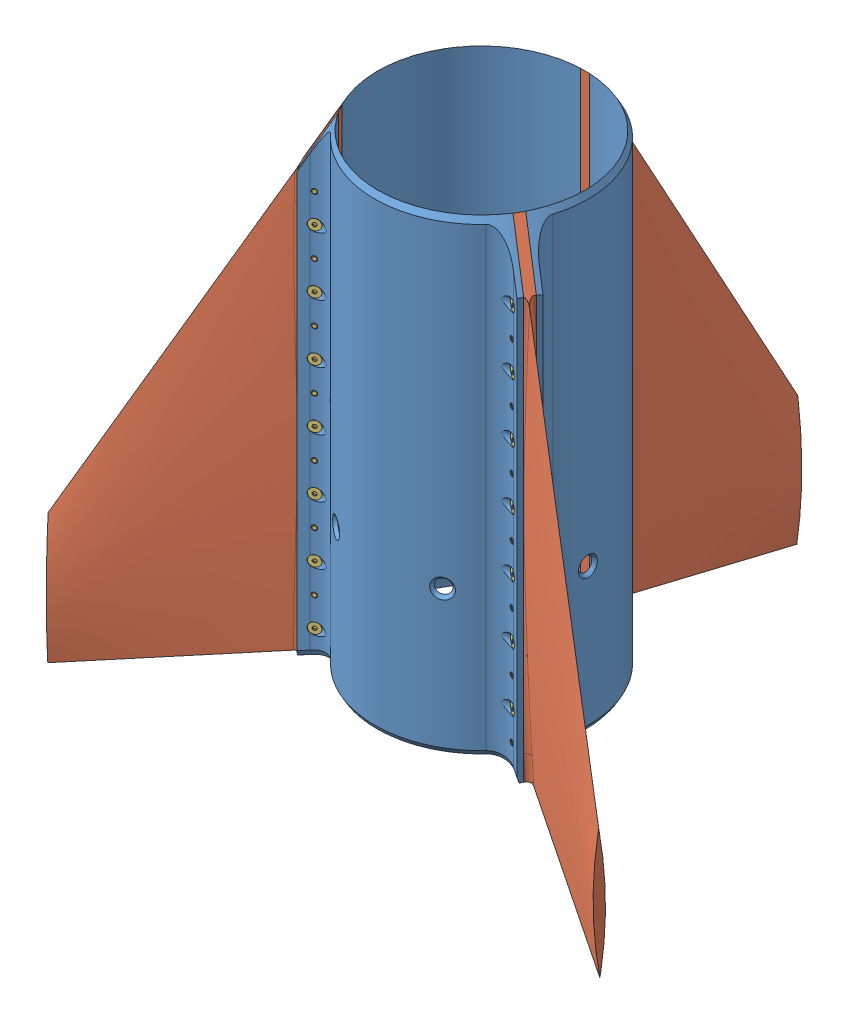
SolidWorks assembly Fin Can 3 Fin Asm Extended, configuration Default. Lengths in mm.
Overall size (544.86 508.03 477.68).
48 component instances, 3 part files, 17 mates.
Components (placement in the parent):
- Binder Fin Can Section 3 - countersink 1 - Extended-1: Binder Fin Can Section 3 - countersink 1 - Extended [Default] at origin size (112.79 464.23 191.15)
- BiconvexFin 3 Fin Fillet Extended-4: BiconvexFin 3 Fin Fillet Extended [Default] at (85.5129 466.7433 54.8816) x (0 -1 0) z (0.866025 0 0.5) size (507.85 12.22 209.48)
- BiconvexFin 3 Fin Fillet Extended-5: BiconvexFin 3 Fin Fillet Extended [Default] at (4.7724 466.7433 -101.4971) x (0 -1 0) z (0 0 -1) size (507.85 12.22 209.48)
- BiconvexFin 3 Fin Fillet Extended-6: BiconvexFin 3 Fin Fillet Extended [Default] at (-90.2852 466.7433 46.6155) x (0 -1 0) z (-0.866025 0 0.5) size (507.85 12.22 209.48)
- Binder Fin Can Section 3 - countersink 1 - Extended-2: Binder Fin Can Section 3 - countersink 1 - Extended [Default] x (-0.5 0 -0.866025) z (0.866025 0 -0.5) size (112.79 464.23 191.15)
- Binder Fin Can Section 3 - countersink 1 - Extended-3: Binder Fin Can Section 3 - countersink 1 - Extended [Default] x (-0.5 0 0.866025) z (-0.866025 0 -0.5) size (112.79 464.23 191.15)
- 91253A008_ 10-32 Black-Oxide Alloy Steel Hex Drive Flat Head Screw-1: 91253A008_ 10-32 Black-Oxide Alloy Steel Hex Drive Flat Head Screw [91253A008] at (0.3377 28.5749 -117.3721) x (0 0 1) z (-1 0 0) size (10.44 10.44 19.55)
- 91253A008_ 10-32 Black-Oxide Alloy Steel Hex Drive Flat Head Screw-2: 91253A008_ 10-32 Black-Oxide Alloy Steel Hex Drive Flat Head Screw [91253A008] at (0.3377 85.7249 -117.3721) x (0 0 1) z (-1 0 0) size (10.44 10.44 19.55)
- 91253A008_ 10-32 Black-Oxide Alloy Steel Hex Drive Flat Head Screw-3: 91253A008_ 10-32 Black-Oxide Alloy Steel Hex Drive Flat Head Screw [91253A008] at (0.3377 142.8749 -117.3721) x (0 0 1) z (-1 0 0) size (10.44 10.44 19.55)
- 91253A008_ 10-32 Black-Oxide Alloy Steel Hex Drive Flat Head Screw-4: 91253A008_ 10-32 Black-Oxide Alloy Steel Hex Drive Flat Head Screw [91253A008] at (0.3377 200.0249 -117.3721) x (0 0 1) z (-1 0 0) size (10.44 10.44 19.55)
- 91253A008_ 10-32 Black-Oxide Alloy Steel Hex Drive Flat Head Screw-28: 91253A008_ 10-32 Black-Oxide Alloy Steel Hex Drive Flat Head Screw [91253A008] at (-0.3377 57.15 -117.3721) x (0 0 1) z (1 0 0) size (10.44 10.44 19.55)
- 91253A008_ 10-32 Black-Oxide Alloy Steel Hex Drive Flat Head Screw-29: 91253A008_ 10-32 Black-Oxide Alloy Steel Hex Drive Flat Head Screw [91253A008] at (-0.3377 114.3 -117.3721) x (0 0 1) z (1 0 0) size (10.44 10.44 19.55)
- 91253A008_ 10-32 Black-Oxide Alloy Steel Hex Drive Flat Head Screw-30: 91253A008_ 10-32 Black-Oxide Alloy Steel Hex Drive Flat Head Screw [91253A008] at (-0.3377 171.45 -117.3721) x (0 0 1) z (1 0 0) size (10.44 10.44 19.55)
- 91253A008_ 10-32 Black-Oxide Alloy Steel Hex Drive Flat Head Screw-31: 91253A008_ 10-32 Black-Oxide Alloy Steel Hex Drive Flat Head Screw [91253A008] at (-0.3377 228.6 -117.3721) x (0 0 1) z (1 0 0) size (10.44 10.44 19.55)
- 91253A008_ 10-32 Black-Oxide Alloy Steel Hex Drive Flat Head Screw-35: 91253A008_ 10-32 Black-Oxide Alloy Steel Hex Drive Flat Head Screw [91253A008] at (101.4783 28.5749 58.9785) x (-0.866025 0 -0.5) z (0.5 0 -0.866025) size (10.44 10.44 19.55)
- 91253A008_ 10-32 Black-Oxide Alloy Steel Hex Drive Flat Head Screw-36: 91253A008_ 10-32 Black-Oxide Alloy Steel Hex Drive Flat Head Screw [91253A008] at (101.4783 85.7249 58.9785) x (-0.866025 0 -0.5) z (0.5 0 -0.866025) size (10.44 10.44 19.55)
- 91253A008_ 10-32 Black-Oxide Alloy Steel Hex Drive Flat Head Screw-37: 91253A008_ 10-32 Black-Oxide Alloy Steel Hex Drive Flat Head Screw [91253A008] at (101.4783 142.8749 58.9785) x (-0.866025 0 -0.5) z (0.5 0 -0.866025) size (10.44 10.44 19.55)
- 91253A008_ 10-32 Black-Oxide Alloy Steel Hex Drive Flat Head Screw-38: 91253A008_ 10-32 Black-Oxide Alloy Steel Hex Drive Flat Head Screw [91253A008] at (101.4783 200.0249 58.9785) x (-0.866025 0 -0.5) z (0.5 0 -0.866025) size (10.44 10.44 19.55)
- 91253A008_ 10-32 Black-Oxide Alloy Steel Hex Drive Flat Head Screw-42: 91253A008_ 10-32 Black-Oxide Alloy Steel Hex Drive Flat Head Screw [91253A008] at (101.8161 57.15 58.3936) x (-0.801823 -0.377852 -0.462933) z (-0.5 0 0.866025) size (10.44 10.44 19.55)
- 91253A008_ 10-32 Black-Oxide Alloy Steel Hex Drive Flat Head Screw-43: 91253A008_ 10-32 Black-Oxide Alloy Steel Hex Drive Flat Head Screw [91253A008] at (101.8161 114.3 58.3936) x (-0.801823 -0.377852 -0.462933) z (-0.5 0 0.866025) size (10.44 10.44 19.55)
- 91253A008_ 10-32 Black-Oxide Alloy Steel Hex Drive Flat Head Screw-44: 91253A008_ 10-32 Black-Oxide Alloy Steel Hex Drive Flat Head Screw [91253A008] at (101.8161 171.45 58.3936) x (-0.801823 -0.377852 -0.462933) z (-0.5 0 0.866025) size (10.44 10.44 19.55)
- 91253A008_ 10-32 Black-Oxide Alloy Steel Hex Drive Flat Head Screw-45: 91253A008_ 10-32 Black-Oxide Alloy Steel Hex Drive Flat Head Screw [91253A008] at (101.8161 228.6 58.3936) x (-0.801823 -0.377852 -0.462933) z (-0.5 0 0.866025) size (10.44 10.44 19.55)
- 91253A008_ 10-32 Black-Oxide Alloy Steel Hex Drive Flat Head Screw-49: 91253A008_ 10-32 Black-Oxide Alloy Steel Hex Drive Flat Head Screw [91253A008] at (-101.8161 28.5749 58.3936) x (-0.801823 -0.377852 0.462933) z (0.5 0 0.866025) size (10.44 10.44 19.55)
- 91253A008_ 10-32 Black-Oxide Alloy Steel Hex Drive Flat Head Screw-50: 91253A008_ 10-32 Black-Oxide Alloy Steel Hex Drive Flat Head Screw [91253A008] at (-101.8161 85.7249 58.3936) x (-0.801823 -0.377852 0.462933) z (0.5 0 0.866025) size (10.44 10.44 19.55)
- 91253A008_ 10-32 Black-Oxide Alloy Steel Hex Drive Flat Head Screw-51: 91253A008_ 10-32 Black-Oxide Alloy Steel Hex Drive Flat Head Screw [91253A008] at (-101.8161 142.8749 58.3936) x (-0.801823 -0.377852 0.462933) z (0.5 0 0.866025) size (10.44 10.44 19.55)
- 91253A008_ 10-32 Black-Oxide Alloy Steel Hex Drive Flat Head Screw-52: 91253A008_ 10-32 Black-Oxide Alloy Steel Hex Drive Flat Head Screw [91253A008] at (-101.8161 200.0249 58.3936) x (-0.801823 -0.377852 0.462933) z (0.5 0 0.866025) size (10.44 10.44 19.55)
- 91253A008_ 10-32 Black-Oxide Alloy Steel Hex Drive Flat Head Screw-56: 91253A008_ 10-32 Black-Oxide Alloy Steel Hex Drive Flat Head Screw [91253A008] at (-101.4783 57.15 58.9785) x (-0.801823 0.377852 0.462933) z (-0.5 0 -0.866025) size (10.44 10.44 19.55)
- 91253A008_ 10-32 Black-Oxide Alloy Steel Hex Drive Flat Head Screw-57: 91253A008_ 10-32 Black-Oxide Alloy Steel Hex Drive Flat Head Screw [91253A008] at (-101.4783 114.3 58.9785) x (-0.801823 0.377852 0.462933) z (-0.5 0 -0.866025) size (10.44 10.44 19.55)
- 91253A008_ 10-32 Black-Oxide Alloy Steel Hex Drive Flat Head Screw-58: 91253A008_ 10-32 Black-Oxide Alloy Steel Hex Drive Flat Head Screw [91253A008] at (-101.4783 171.45 58.9785) x (-0.801823 0.377852 0.462933) z (-0.5 0 -0.866025) size (10.44 10.44 19.55)
- 91253A008_ 10-32 Black-Oxide Alloy Steel Hex Drive Flat Head Screw-59: 91253A008_ 10-32 Black-Oxide Alloy Steel Hex Drive Flat Head Screw [91253A008] at (-101.4783 228.6 58.9785) x (-0.801823 0.377852 0.462933) z (-0.5 0 -0.866025) size (10.44 10.44 19.55)
- 91253A008_ 10-32 Black-Oxide Alloy Steel Hex Drive Flat Head Screw-25: 91253A008_ 10-32 Black-Oxide Alloy Steel Hex Drive Flat Head Screw [91253A008] at (0.3377 257.1749 -117.3721) x (0 0 1) z (-1 0 0) size (10.44 10.44 19.55)
- 91253A008_ 10-32 Black-Oxide Alloy Steel Hex Drive Flat Head Screw-26: 91253A008_ 10-32 Black-Oxide Alloy Steel Hex Drive Flat Head Screw [91253A008] at (0.3377 314.3249 -117.3721) x (0 0 1) z (-1 0 0) size (10.44 10.44 19.55)
- 91253A008_ 10-32 Black-Oxide Alloy Steel Hex Drive Flat Head Screw-27: 91253A008_ 10-32 Black-Oxide Alloy Steel Hex Drive Flat Head Screw [91253A008] at (0.3377 371.4749 -117.3721) x (0 0 1) z (-1 0 0) size (10.44 10.44 19.55)
- 91253A008_ 10-32 Black-Oxide Alloy Steel Hex Drive Flat Head Screw-32: 91253A008_ 10-32 Black-Oxide Alloy Steel Hex Drive Flat Head Screw [91253A008] at (-0.3377 285.75 -117.3721) x (0 0 1) z (1 0 0) size (10.44 10.44 19.55)
- 91253A008_ 10-32 Black-Oxide Alloy Steel Hex Drive Flat Head Screw-33: 91253A008_ 10-32 Black-Oxide Alloy Steel Hex Drive Flat Head Screw [91253A008] at (-0.3377 342.9 -117.3721) x (0 0 1) z (1 0 0) size (10.44 10.44 19.55)
- 91253A008_ 10-32 Black-Oxide Alloy Steel Hex Drive Flat Head Screw-34: 91253A008_ 10-32 Black-Oxide Alloy Steel Hex Drive Flat Head Screw [91253A008] at (-0.3377 400.05 -117.3721) x (0 0 1) z (1 0 0) size (10.44 10.44 19.55)
- 91253A008_ 10-32 Black-Oxide Alloy Steel Hex Drive Flat Head Screw-39: 91253A008_ 10-32 Black-Oxide Alloy Steel Hex Drive Flat Head Screw [91253A008] at (101.4783 257.1749 58.9785) x (-0.866025 0 -0.5) z (0.5 0 -0.866025) size (10.44 10.44 19.55)
- 91253A008_ 10-32 Black-Oxide Alloy Steel Hex Drive Flat Head Screw-40: 91253A008_ 10-32 Black-Oxide Alloy Steel Hex Drive Flat Head Screw [91253A008] at (101.4783 314.3249 58.9785) x (-0.866025 0 -0.5) z (0.5 0 -0.866025) size (10.44 10.44 19.55)
- 91253A008_ 10-32 Black-Oxide Alloy Steel Hex Drive Flat Head Screw-41: 91253A008_ 10-32 Black-Oxide Alloy Steel Hex Drive Flat Head Screw [91253A008] at (101.4783 371.4749 58.9785) x (-0.866025 0 -0.5) z (0.5 0 -0.866025) size (10.44 10.44 19.55)
- 91253A008_ 10-32 Black-Oxide Alloy Steel Hex Drive Flat Head Screw-46: 91253A008_ 10-32 Black-Oxide Alloy Steel Hex Drive Flat Head Screw [91253A008] at (101.8161 285.75 58.3936) x (-0.801823 -0.377852 -0.462933) z (-0.5 0 0.866025) size (10.44 10.44 19.55)
- 91253A008_ 10-32 Black-Oxide Alloy Steel Hex Drive Flat Head Screw-47: 91253A008_ 10-32 Black-Oxide Alloy Steel Hex Drive Flat Head Screw [91253A008] at (101.8161 342.9 58.3936) x (-0.801823 -0.377852 -0.462933) z (-0.5 0 0.866025) size (10.44 10.44 19.55)
- 91253A008_ 10-32 Black-Oxide Alloy Steel Hex Drive Flat Head Screw-48: 91253A008_ 10-32 Black-Oxide Alloy Steel Hex Drive Flat Head Screw [91253A008] at (101.8161 400.05 58.3936) x (-0.801823 -0.377852 -0.462933) z (-0.5 0 0.866025) size (10.44 10.44 19.55)
- 91253A008_ 10-32 Black-Oxide Alloy Steel Hex Drive Flat Head Screw-53: 91253A008_ 10-32 Black-Oxide Alloy Steel Hex Drive Flat Head Screw [91253A008] at (-101.8161 257.1749 58.3936) x (-0.801823 -0.377852 0.462933) z (0.5 0 0.866025) size (10.44 10.44 19.55)
- 91253A008_ 10-32 Black-Oxide Alloy Steel Hex Drive Flat Head Screw-54: 91253A008_ 10-32 Black-Oxide Alloy Steel Hex Drive Flat Head Screw [91253A008] at (-101.8161 314.3249 58.3936) x (-0.801823 -0.377852 0.462933) z (0.5 0 0.866025) size (10.44 10.44 19.55)
- 91253A008_ 10-32 Black-Oxide Alloy Steel Hex Drive Flat Head Screw-55: 91253A008_ 10-32 Black-Oxide Alloy Steel Hex Drive Flat Head Screw [91253A008] at (-101.8161 371.4749 58.3936) x (-0.801823 -0.377852 0.462933) z (0.5 0 0.866025) size (10.44 10.44 19.55)
- 91253A008_ 10-32 Black-Oxide Alloy Steel Hex Drive Flat Head Screw-60: 91253A008_ 10-32 Black-Oxide Alloy Steel Hex Drive Flat Head Screw [91253A008] at (-101.4783 285.75 58.9785) x (-0.801823 0.377852 0.462933) z (-0.5 0 -0.866025) size (10.44 10.44 19.55)
- 91253A008_ 10-32 Black-Oxide Alloy Steel Hex Drive Flat Head Screw-61: 91253A008_ 10-32 Black-Oxide Alloy Steel Hex Drive Flat Head Screw [91253A008] at (-101.4783 342.9 58.9785) x (-0.801823 0.377852 0.462933) z (-0.5 0 -0.866025) size (10.44 10.44 19.55)
- 91253A008_ 10-32 Black-Oxide Alloy Steel Hex Drive Flat Head Screw-62: 91253A008_ 10-32 Black-Oxide Alloy Steel Hex Drive Flat Head Screw [91253A008] at (-101.4783 400.05 58.9785) x (-0.801823 0.377852 0.462933) z (-0.5 0 -0.866025) size (10.44 10.44 19.55)
Mates (geometry in assembly coordinates):
- Coincident1: coincident anti-aligned: plane of Binder Fin Can Section 3 - countersink 1 - Extended-1 through (90.185 508 46.7891) normal (-0.5 0 0.866025); plane of BiconvexFin 3 Fin Fillet Extended-4 through (559.9421 490.99 318.0034) normal (0.5 0 -0.866025)
- Coincident2: coincident aligned: plane of Binder Fin Can Section 3 - countersink 1 - Extended-1 through (117.313 508 56.9521) normal (0.866025 0 0.5); plane of BiconvexFin 3 Fin Fillet Extended-4 through (110.2252 466.7433 69.2286) normal (0.866025 0 0.5)
- Concentric1: concentric aligned: cylinder of Binder Fin Can Section 3 - countersink 1 - Extended-1 through (103.9332 28.5749 54.7266) axis (-0.5 0 0.866025) radius 2.4892; cylinder of BiconvexFin 3 Fin Fillet Extended-4 through (99.3612 28.5749 62.6455) axis (-0.5 0 0.866025) radius 2.4892
- Concentric2: concentric: cylinder of Binder Fin Can Section 3 - countersink 1 - Extended-2 through (-4.572 28.5749 -117.3721) axis (1 0 0) radius 2.4892; circle of 92210A197_18-8 8-32 Stainless Steel Hex Drive Flat Head Screw-1
- Coincident3: coincident aligned: cone of Binder Fin Can Section 3 - countersink 1 - Extended-2 through (-3.1182 28.5749 -117.3721) axis (1 0 0); cone of 92210A197_18-8 8-32 Stainless Steel Hex Drive Flat Head Screw-1 through (-5.5498 34.9247 -114.2076) axis (1 0 0)
- Concentric3: concentric aligned: cylinder of Binder Fin Can Section 3 - countersink 1 - Extended-2 through (-4.572 28.5749 -117.3721) axis (1 0 0) radius 2.4892; circle of 92210A304_18-8 10-32 Stainless Steel Hex Drive Flat Head Screw-1
- Coincident4: coincident aligned: cone of Binder Fin Can Section 3 - countersink 1 - Extended-2 through (-3.1182 28.5749 -117.3721) axis (1 0 0); cone of 91253A008_ 10-32 Black-Oxide Alloy Steel Hex Drive Flat Head Screw-1 through (-5.9615 28.5749 -117.3721) axis (1 0 0)
- Concentric4: concentric aligned: cylinder of Binder Fin Can Section 3 - countersink 1 - Extended-1 through (4.572 57.15 -117.3721) axis (-1 0 0) radius 2.4892; circle of 92210A304_18-8 10-32 Stainless Steel Hex Drive Flat Head Screw-5
- Coincident5: coincident aligned: cone of Binder Fin Can Section 3 - countersink 1 - Extended-1 through (17.3602 57.15 -117.3721) axis (-1 0 0); cone of 91253A008_ 10-32 Black-Oxide Alloy Steel Hex Drive Flat Head Screw-28 through (5.9615 57.15 -117.3721) axis (-1 0 0)
- Concentric5: concentric aligned: cylinder of Binder Fin Can Section 3 - countersink 1 - Extended-1 through (103.9332 28.5749 54.7266) axis (-0.5 0 0.866025) radius 2.4892; circle of 92210A304_18-8 10-32 Stainless Steel Hex Drive Flat Head Screw-9
- Coincident6: coincident aligned: cone of Binder Fin Can Section 3 - countersink 1 - Extended-1 through (103.2063 28.5749 55.9856) axis (-0.5 0 0.866025); cone of 91253A008_ 10-32 Black-Oxide Alloy Steel Hex Drive Flat Head Screw-35 through (104.6279 28.5749 53.5232) axis (-0.5 0 0.866025)
- Concentric6: concentric aligned: cylinder of Binder Fin Can Section 3 - countersink 1 - Extended-3 through (99.3612 57.15 62.6455) axis (0.5 0 -0.866025) radius 2.4892; circle of 92210A304_18-8 10-32 Stainless Steel Hex Drive Flat Head Screw-13
- Coincident7: coincident aligned: cone of Binder Fin Can Section 3 - countersink 1 - Extended-3 through (92.9671 57.15 73.7204) axis (0.5 0 -0.866025); cone of 91253A008_ 10-32 Black-Oxide Alloy Steel Hex Drive Flat Head Screw-42 through (98.6665 57.15 63.8488) axis (0.5 0 -0.866025)
- Concentric7: concentric aligned: cylinder of Binder Fin Can Section 3 - countersink 1 - Extended-3 through (-99.3612 28.5749 62.6455) axis (-0.5 0 -0.866025) radius 2.4892; circle of 92210A304_18-8 10-32 Stainless Steel Hex Drive Flat Head Screw-17
- Coincident8: coincident aligned: cone of Binder Fin Can Section 3 - countersink 1 - Extended-3 through (-100.0881 28.5749 61.3865) axis (-0.5 0 -0.866025); cone of 91253A008_ 10-32 Black-Oxide Alloy Steel Hex Drive Flat Head Screw-49 through (-98.6665 28.5749 63.8488) axis (-0.5 0 -0.866025)
- Concentric8: concentric aligned: cylinder of Binder Fin Can Section 3 - countersink 1 - Extended-2 through (-103.9332 57.15 54.7266) axis (0.5 0 0.866025) radius 2.4892; circle of 92210A304_18-8 10-32 Stainless Steel Hex Drive Flat Head Screw-21
- Coincident12: coincident aligned: cone of Binder Fin Can Section 3 - countersink 1 - Extended-2 through (-110.3273 57.15 43.6517) axis (0.5 0 0.866025); cone of 91253A008_ 10-32 Black-Oxide Alloy Steel Hex Drive Flat Head Screw-56 through (-104.6279 57.15 53.5232) axis (0.5 0 0.866025)
